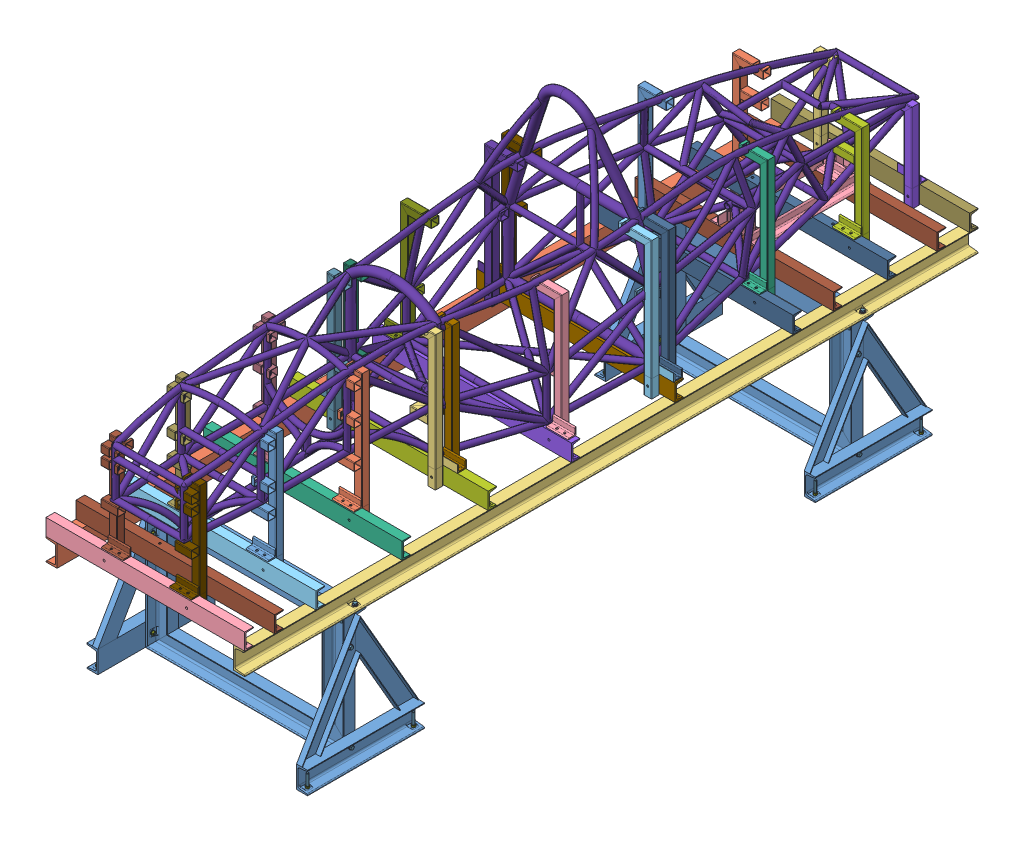
SolidWorks assembly FrameOnMainJig, configuration Default. Lengths in mm.
Overall size (1444.14 1755.21 3568.16).
235 component instances, 41 part files, 62 mates.
Components (placement in the parent):
- MainJig-1: MainJig [Default] at origin size (1000 753.95 3322.05)
  - MainJigLegs-1: MainJigLegs [Default<As Machined>] at origin size (1000 560 530)
  - MainJigLegs-2: MainJigLegs [Default<As Machined>] at (0 0 2300) size (1000 560 530)
  - MainJigLongRailRight-1: MainJigLongRailRight [Default<As Machined>] at (-400 50 2270) x (0 0 -1) z (1 0 0) size (3322 100 50)
  - MainJigLongRailLeft-1: MainJigLongRailLeft [Default<As Machined>] at (400 50 2270) x (0 0 -1) z (1 0 0) size (3322 100 50)
  - MainJigCrossRailA-1: MainJigCrossRailA [Default<As Machined>] at (0 137.5 2800) size (900 75 40)
  - MainJigCrossRailC-2: MainJigCrossRailC [Default<As Machined>] at (0 137.5 2477) size (900 75 40)
  - MainJigCrossRailD-3: MainJigCrossRailD [Default<As Machined>] at (0 137.5 2087.1) size (900 75 40)
  - MainJigCrossRailE-4: MainJigCrossRailE [Default<As Machined>] at (0 138.1 1697) size (900 76.2 38.05)
  - MainJigCrossRailF-5: MainJigCrossRailF [Default<As Machined>] at (0 138.1 1320) size (900 76.2 38.05)
  - MainJigCrossRailG-6: MainJigCrossRailG [Default<As Machined>] at (0 138.1 850) size (900 76.2 38.05)
  - MainJigCrossRailH-7: MainJigCrossRailH [Default<As Machined>] at (0 138.1 316.2) size (900 76.2 38.05)
  - MainJigCrossRail-8: MainJigCrossRail [Default<As Machined>] at (0 137.5 2664.3) size (900 75 40)
  - MainJigCrossRail-9: MainJigCrossRail [Default<As Machined>] at (0 137.5 132.6) size (900 75 40)
  - MainJigCrossRailH-10: MainJigCrossRailH [Default<As Machined>] at (0 138.1 -112.5) size (900 76.2 38.05)
  - MainJigCrossRail-11: MainJigCrossRail [Default<As Machined>] at (0 137.5 -336.9) size (900 75 40)
  - MainJigCrossRailL-12: MainJigCrossRailL [Default<As Machined>] at (0 138.1 -484) size (900 76.2 38.05)
  - Flat Washer Type A Narrow_AI-36: Flat Washer Type A Narrow_AI [Preferred Narrow FW 0.375] at (425 105 2780) x (0 -1 0) z (0 0 1) size (1.65 20.62 20.62)
  - Flat Washer Type A Narrow_AI-37: Flat Washer Type A Narrow_AI [Preferred Narrow FW 0.375] at (425 104 2457) x (0 -1 0) z (0 0 1) size (1.65 20.62 20.62)
  - Flat Washer Type A Narrow_AI-38: Flat Washer Type A Narrow_AI [Preferred Narrow FW 0.375] at (425 105 2067.1) x (0 -1 0) z (0 0 1) size (1.65 20.62 20.62)
  - Flat Washer Type A Narrow_AI-39: Flat Washer Type A Narrow_AI [Preferred Narrow FW 0.375] at (425 105 1677) x (0 -1 0) z (0 0 1) size (1.65 20.62 20.62)
  - Flat Washer Type A Narrow_AI-40: Flat Washer Type A Narrow_AI [Preferred Narrow FW 0.375] at (425 105 1300) x (0 -1 0) z (0 0 1) size (1.65 20.62 20.62)
  - Flat Washer Type A Narrow_AI-41: Flat Washer Type A Narrow_AI [Preferred Narrow FW 0.375] at (425 105 830) x (0 -1 0) z (0 0 1) size (1.65 20.62 20.62)
  - Flat Washer Type A Narrow_AI-42: Flat Washer Type A Narrow_AI [Preferred Narrow FW 0.375] at (425 105 2644.3) x (0 -1 0) z (0 0 1) size (1.65 20.62 20.62)
  - Flat Washer Type A Narrow_AI-43: Flat Washer Type A Narrow_AI [Preferred Narrow FW 0.375] at (425 105 296.2) x (0 -1 0) z (0 0 1) size (1.65 20.62 20.62)
  - Flat Washer Type A Narrow_AI-44: Flat Washer Type A Narrow_AI [Preferred Narrow FW 0.375] at (425 104.6 112.6) x (0 -1 0) z (0 0 1) size (1.65 20.62 20.62)
  - Flat Washer Type A Narrow_AI-45: Flat Washer Type A Narrow_AI [Preferred Narrow FW 0.375] at (425 105 -132.5) x (0 -1 0) z (0 0 1) size (1.65 20.62 20.62)
  - Flat Washer Type A Narrow_AI-46: Flat Washer Type A Narrow_AI [Preferred Narrow FW 0.375] at (425 104 -356.9) x (0 -1 0) z (0 0 1) size (1.65 20.62 20.62)
  - Flat Washer Type A Narrow_AI-48: Flat Washer Type A Narrow_AI [Preferred Narrow FW 0.375] at (425 105 -504) x (0 -1 0) z (0 0 1) size (1.65 20.62 20.62)
  - Flat Washer Type A Narrow_AI-49: Flat Washer Type A Narrow_AI [Preferred Narrow FW 0.375] at (-425 105 2780) x (0 -1 0) z (0 0 1) size (1.65 20.62 20.62)
  - Flat Washer Type A Narrow_AI-50: Flat Washer Type A Narrow_AI [Preferred Narrow FW 0.375] at (-425 105 2457) x (0 -1 0) z (0 0 1) size (1.65 20.62 20.62)
  - Flat Washer Type A Narrow_AI-51: Flat Washer Type A Narrow_AI [Preferred Narrow FW 0.375] at (-425 105 2067.1) x (0 -1 0) z (0 0 1) size (1.65 20.62 20.62)
  - Flat Washer Type A Narrow_AI-52: Flat Washer Type A Narrow_AI [Preferred Narrow FW 0.375] at (-425 105 1677) x (0 -1 0) z (0 0 1) size (1.65 20.62 20.62)
  - Flat Washer Type A Narrow_AI-53: Flat Washer Type A Narrow_AI [Preferred Narrow FW 0.375] at (-425 105 1300) x (0 -1 0) z (0 0 1) size (1.65 20.62 20.62)
  - Flat Washer Type A Narrow_AI-54: Flat Washer Type A Narrow_AI [Preferred Narrow FW 0.375] at (-425 105 830) x (0 -1 0) z (0 0 1) size (1.65 20.62 20.62)
  - Flat Washer Type A Narrow_AI-56: Flat Washer Type A Narrow_AI [Preferred Narrow FW 0.375] at (-425 105 2644.3) x (0 -1 0) z (0 0 1) size (1.65 20.62 20.62)
  - Flat Washer Type A Narrow_AI-57: Flat Washer Type A Narrow_AI [Preferred Narrow FW 0.375] at (-425 105 296.2) x (0 -1 0) z (0 0 1) size (1.65 20.62 20.62)
  - Flat Washer Type A Narrow_AI-58: Flat Washer Type A Narrow_AI [Preferred Narrow FW 0.375] at (-425 104.6 112.6) x (0 -1 0) z (0 0 1) size (1.65 20.62 20.62)
  - Flat Washer Type A Narrow_AI-59: Flat Washer Type A Narrow_AI [Preferred Narrow FW 0.375] at (-425 105 -132.5) x (0 -1 0) z (0 0 1) size (1.65 20.62 20.62)
  - Flat Washer Type A Narrow_AI-60: Flat Washer Type A Narrow_AI [Preferred Narrow FW 0.375] at (-425 104 -356.9) x (0 -1 0) z (0 0 1) size (1.65 20.62 20.62)
  - Flat Washer Type A Narrow_AI-61: Flat Washer Type A Narrow_AI [Preferred Narrow FW 0.375] at (-425 105 -504) x (0 -1 0) z (0 0 1) size (1.65 20.62 20.62)
  - Hex Bolt_AI-17: Hex Bolt_AI [HBOLT 0.3750-16x1.25x1-N] at (425 113.4582 2780) x (0 -1 0) z (0 0 1) size (38.56 16.48 14.27)
  - Hex Bolt_AI-18: Hex Bolt_AI [HBOLT 0.3750-16x1.25x1-N] at (425 112.4582 2457) x (0 -1 0) z (0 0 1) size (38.56 16.48 14.27)
  - Hex Bolt_AI-19: Hex Bolt_AI [HBOLT 0.3750-16x1.25x1-N] at (425 113.4582 2067.1) x (0 -1 0) z (0 0 1) size (38.56 16.48 14.27)
  - Hex Bolt_AI-20: Hex Bolt_AI [HBOLT 0.3750-16x1.25x1-N] at (425 113.4582 1677) x (0 -1 0) z (0 0 1) size (38.56 16.48 14.27)
  - Hex Bolt_AI-21: Hex Bolt_AI [HBOLT 0.3750-16x1.25x1-N] at (425 113.4582 1300) x (0 -1 0) z (0 0 1) size (38.56 16.48 14.27)
  - Hex Bolt_AI-22: Hex Bolt_AI [HBOLT 0.3750-16x1.25x1-N] at (425 113.4582 830) x (0 -1 0) z (0 0 1) size (38.56 16.48 14.27)
  - Hex Bolt_AI-23: Hex Bolt_AI [HBOLT 0.3750-16x1.25x1-N] at (425 113.4582 2644.3) x (0 -1 0) z (0 0 1) size (38.56 16.48 14.27)
  - Hex Bolt_AI-24: Hex Bolt_AI [HBOLT 0.3750-16x1.25x1-N] at (425 113.4582 296.2) x (0 -1 0) z (0 0 1) size (38.56 16.48 14.27)
  - Hex Bolt_AI-25: Hex Bolt_AI [HBOLT 0.3750-16x1.25x1-N] at (425 113.0582 112.6) x (0 -1 0) z (0 0 1) size (38.56 16.48 14.27)
  - Hex Bolt_AI-26: Hex Bolt_AI [HBOLT 0.3750-16x1.25x1-N] at (425 113.4582 -132.5) x (0 -1 0) z (0 0 1) size (38.56 16.48 14.27)
  - Hex Bolt_AI-27: Hex Bolt_AI [HBOLT 0.3750-16x1.25x1-N] at (425 112.4582 -356.9) x (0 -1 0) z (0 0 1) size (38.56 16.48 14.27)
  - Hex Bolt_AI-28: Hex Bolt_AI [HBOLT 0.3750-16x1.25x1-N] at (425 113.4582 -504) x (0 -1 0) z (0 0 1) size (38.56 16.48 14.27)
  - Hex Bolt_AI-29: Hex Bolt_AI [HBOLT 0.3750-16x1.25x1-N] at (-425 113.4582 2780) x (0 -1 0) z (0 0 1) size (38.56 16.48 14.27)
  - Hex Bolt_AI-30: Hex Bolt_AI [HBOLT 0.3750-16x1.25x1-N] at (-425 113.4582 2457) x (0 -1 0) z (0 0 1) size (38.56 16.48 14.27)
  - Hex Bolt_AI-31: Hex Bolt_AI [HBOLT 0.3750-16x1.25x1-N] at (-425 113.4582 2067.1) x (0 -1 0) z (0 0 1) size (38.56 16.48 14.27)
  - Hex Bolt_AI-32: Hex Bolt_AI [HBOLT 0.3750-16x1.25x1-N] at (-425 113.4582 1677) x (0 -1 0) z (0 0 1) size (38.56 16.48 14.27)
  - Hex Bolt_AI-33: Hex Bolt_AI [HBOLT 0.3750-16x1.25x1-N] at (-425 113.4582 1300) x (0 -1 0) z (0 0 1) size (38.56 16.48 14.27)
  - Hex Bolt_AI-34: Hex Bolt_AI [HBOLT 0.3750-16x1.25x1-N] at (-425 113.4582 830) x (0 -1 0) z (0 0 1) size (38.56 16.48 14.27)
  - Hex Bolt_AI-35: Hex Bolt_AI [HBOLT 0.3750-16x1.25x1-N] at (-425 113.4582 2644.3) x (0 -1 0) z (0 0 1) size (38.56 16.48 14.27)
  - Hex Bolt_AI-36: Hex Bolt_AI [HBOLT 0.3750-16x1.25x1-N] at (-425 113.4582 296.2) x (0 -1 0) z (0 0 1) size (38.56 16.48 14.27)
  - Hex Bolt_AI-37: Hex Bolt_AI [HBOLT 0.3750-16x1.25x1-N] at (-425 113.0582 112.6) x (0 -1 0) z (0 0 1) size (38.56 16.48 14.27)
  - Hex Bolt_AI-38: Hex Bolt_AI [HBOLT 0.3750-16x1.25x1-N] at (-425 113.4582 -132.5) x (0 -1 0) z (0 0 1) size (38.56 16.48 14.27)
  - Hex Bolt_AI-39: Hex Bolt_AI [HBOLT 0.3750-16x1.25x1-N] at (-425 112.4582 -356.9) x (0 -1 0) z (0 0 1) size (38.56 16.48 14.27)
  - Hex Bolt_AI-40: Hex Bolt_AI [HBOLT 0.3750-16x1.25x1-N] at (-425 113.4582 -504) x (0 -1 0) z (0 0 1) size (38.56 16.48 14.27)
  - Lock Washer Spring Regular_AI-68: Lock Washer Spring Regular_AI [Regular LW 0.375] at (425 93 2780) x (0 1 0) z (0 0 1) size (2.39 17.35 17.32)
  - Lock Washer Spring Regular_AI-69: Lock Washer Spring Regular_AI [Regular LW 0.375] at (425 93 2644.3) x (0 1 0) z (0 0 1) size (2.39 17.35 17.32)
  - Lock Washer Spring Regular_AI-70: Lock Washer Spring Regular_AI [Regular LW 0.375] at (425 93 2457) x (0 1 0) z (0 0 1) size (2.39 17.35 17.32)
  - Lock Washer Spring Regular_AI-71: Lock Washer Spring Regular_AI [Regular LW 0.375] at (425 93 2067.1) x (0 1 0) z (0 0 1) size (2.39 17.35 17.32)
  - Lock Washer Spring Regular_AI-72: Lock Washer Spring Regular_AI [Regular LW 0.375] at (425 93 1677) x (0 1 0) z (0 0 1) size (2.39 17.35 17.32)
  - Lock Washer Spring Regular_AI-73: Lock Washer Spring Regular_AI [Regular LW 0.375] at (425 93 1300) x (0 1 0) z (0 0 1) size (2.39 17.35 17.32)
  - Lock Washer Spring Regular_AI-74: Lock Washer Spring Regular_AI [Regular LW 0.375] at (425 93 830) x (0 1 0) z (0 0 1) size (2.39 17.35 17.32)
  - Lock Washer Spring Regular_AI-75: Lock Washer Spring Regular_AI [Regular LW 0.375] at (425 93 296.2) x (0 1 0) z (0 0 1) size (2.39 17.35 17.32)
  - Lock Washer Spring Regular_AI-76: Lock Washer Spring Regular_AI [Regular LW 0.375] at (425 93 112.6) x (0 1 0) z (0 0 1) size (2.39 17.35 17.32)
  - Lock Washer Spring Regular_AI-78: Lock Washer Spring Regular_AI [Regular LW 0.375] at (425 93 -132.5) x (0 1 0) z (0 0 1) size (2.39 17.35 17.32)
  - Lock Washer Spring Regular_AI-79: Lock Washer Spring Regular_AI [Regular LW 0.375] at (425 93 -356.9) x (0 1 0) z (0 0 1) size (2.39 17.35 17.32)
  - Lock Washer Spring Regular_AI-80: Lock Washer Spring Regular_AI [Regular LW 0.375] at (425 93 -504) x (0 1 0) z (0 0 1) size (2.39 17.35 17.32)
  - Lock Washer Spring Regular_AI-81: Lock Washer Spring Regular_AI [Regular LW 0.375] at (-425 93 2780) x (0 1 0) z (0 0 1) size (2.39 17.35 17.32)
  - Lock Washer Spring Regular_AI-82: Lock Washer Spring Regular_AI [Regular LW 0.375] at (-425 93 2644.3) x (0 1 0) z (0 0 1) size (2.39 17.35 17.32)
  - Lock Washer Spring Regular_AI-83: Lock Washer Spring Regular_AI [Regular LW 0.375] at (-425 93 2457) x (0 1 0) z (0 0 1) size (2.39 17.35 17.32)
  - Lock Washer Spring Regular_AI-84: Lock Washer Spring Regular_AI [Regular LW 0.375] at (-425 93 2067.1) x (0 1 0) z (0 0 1) size (2.39 17.35 17.32)
  - Lock Washer Spring Regular_AI-85: Lock Washer Spring Regular_AI [Regular LW 0.375] at (-425 93 1677) x (0 1 0) z (0 0 1) size (2.39 17.35 17.32)
  - Lock Washer Spring Regular_AI-86: Lock Washer Spring Regular_AI [Regular LW 0.375] at (-425 93 1300) x (0 1 0) z (0 0 1) size (2.39 17.35 17.32)
  - Lock Washer Spring Regular_AI-87: Lock Washer Spring Regular_AI [Regular LW 0.375] at (-425 93 830) x (0 1 0) z (0 0 1) size (2.39 17.35 17.32)
  - Lock Washer Spring Regular_AI-88: Lock Washer Spring Regular_AI [Regular LW 0.375] at (-425 93 296.2) x (0 1 0) z (0 0 1) size (2.39 17.35 17.32)
  - Lock Washer Spring Regular_AI-89: Lock Washer Spring Regular_AI [Regular LW 0.375] at (-425 93 112.6) x (0 1 0) z (0 0 1) size (2.39 17.35 17.32)
  - Lock Washer Spring Regular_AI-90: Lock Washer Spring Regular_AI [Regular LW 0.375] at (-425 93 -132.5) x (0 1 0) z (0 0 1) size (2.39 17.35 17.32)
  - Lock Washer Spring Regular_AI-91: Lock Washer Spring Regular_AI [Regular LW 0.375] at (-425 93 -356.9) x (0 1 0) z (0 0 1) size (2.39 17.35 17.32)
  - Lock Washer Spring Regular_AI-92: Lock Washer Spring Regular_AI [Regular LW 0.375] at (-425 93 -504) x (0 1 0) z (0 0 1) size (2.39 17.35 17.32)
  - Hex Nut_AI-92: Hex Nut_AI [HNUT 0.3750-16-D-N] at (425 82.0526 2780) x (1 0 0) z (0 -1 0) size (14.27 16.48 8.56)
  - Hex Nut_AI-93: Hex Nut_AI [HNUT 0.3750-16-D-N] at (425 82.0526 2644.3) x (1 0 0) z (0 -1 0) size (14.27 16.48 8.56)
  - Hex Nut_AI-94: Hex Nut_AI [HNUT 0.3750-16-D-N] at (425 82.0526 2457) x (1 0 0) z (0 -1 0) size (14.27 16.48 8.56)
  - Hex Nut_AI-95: Hex Nut_AI [HNUT 0.3750-16-D-N] at (425 82.0526 2067.1) x (1 0 0) z (0 -1 0) size (14.27 16.48 8.56)
  - Hex Nut_AI-96: Hex Nut_AI [HNUT 0.3750-16-D-N] at (425 82.0526 1677) x (1 0 0) z (0 -1 0) size (14.27 16.48 8.56)
  - Hex Nut_AI-97: Hex Nut_AI [HNUT 0.3750-16-D-N] at (425 82.0526 1300) x (1 0 0) z (0 -1 0) size (14.27 16.48 8.56)
  - Hex Nut_AI-98: Hex Nut_AI [HNUT 0.3750-16-D-N] at (425 82.0526 830) x (1 0 0) z (0 -1 0) size (14.27 16.48 8.56)
  - Hex Nut_AI-99: Hex Nut_AI [HNUT 0.3750-16-D-N] at (425 82.0526 296.2) x (1 0 0) z (0 -1 0) size (14.27 16.48 8.56)
  - Hex Nut_AI-100: Hex Nut_AI [HNUT 0.3750-16-D-N] at (425 82.0526 112.6) x (1 0 0) z (0 -1 0) size (14.27 16.48 8.56)
  - Hex Nut_AI-101: Hex Nut_AI [HNUT 0.3750-16-D-N] at (425 82.0526 -132.5) x (1 0 0) z (0 -1 0) size (14.27 16.48 8.56)
  - Hex Nut_AI-102: Hex Nut_AI [HNUT 0.3750-16-D-N] at (425 82.0526 -356.9) x (1 0 0) z (0 -1 0) size (14.27 16.48 8.56)
  - Hex Nut_AI-103: Hex Nut_AI [HNUT 0.3750-16-D-N] at (425 82.0526 -504) x (1 0 0) z (0 -1 0) size (14.27 16.48 8.56)
  - Hex Nut_AI-104: Hex Nut_AI [HNUT 0.3750-16-D-N] at (-425 82.0526 2780) x (1 0 0) z (0 -1 0) size (14.27 16.48 8.56)
  - Hex Nut_AI-105: Hex Nut_AI [HNUT 0.3750-16-D-N] at (-425 82.0526 2644.3) x (1 0 0) z (0 -1 0) size (14.27 16.48 8.56)
  - Hex Nut_AI-106: Hex Nut_AI [HNUT 0.3750-16-D-N] at (-425 82.0526 2457) x (1 0 0) z (0 -1 0) size (14.27 16.48 8.56)
  - Hex Nut_AI-107: Hex Nut_AI [HNUT 0.3750-16-D-N] at (-425 82.0526 2067.1) x (1 0 0) z (0 -1 0) size (14.27 16.48 8.56)
  - Hex Nut_AI-108: Hex Nut_AI [HNUT 0.3750-16-D-N] at (-425 82.0526 1677) x (1 0 0) z (0 -1 0) size (14.27 16.48 8.56)
  - Hex Nut_AI-109: Hex Nut_AI [HNUT 0.3750-16-D-N] at (-425 82.0526 1300) x (1 0 0) z (0 -1 0) size (14.27 16.48 8.56)
  - Hex Nut_AI-110: Hex Nut_AI [HNUT 0.3750-16-D-N] at (-425 82.0526 830) x (1 0 0) z (0 -1 0) size (14.27 16.48 8.56)
  - Hex Nut_AI-111: Hex Nut_AI [HNUT 0.3750-16-D-N] at (-425 82.0526 296.2) x (1 0 0) z (0 -1 0) size (14.27 16.48 8.56)
  - Hex Nut_AI-112: Hex Nut_AI [HNUT 0.3750-16-D-N] at (-425 82.0526 112.6) x (1 0 0) z (0 -1 0) size (14.27 16.48 8.56)
  - Hex Nut_AI-113: Hex Nut_AI [HNUT 0.3750-16-D-N] at (-425 82.0526 -132.5) x (1 0 0) z (0 -1 0) size (14.27 16.48 8.56)
  - Hex Nut_AI-114: Hex Nut_AI [HNUT 0.3750-16-D-N] at (-425 82.0526 -356.9) x (1 0 0) z (0 -1 0) size (14.27 16.48 8.56)
  - Hex Nut_AI-115: Hex Nut_AI [HNUT 0.3750-16-D-N] at (-425 82.0526 -504) x (1 0 0) z (0 -1 0) size (14.27 16.48 8.56)
  - Flat Washer Type A Narrow_AI-62: Flat Washer Type A Narrow_AI [Preferred Narrow FW 0.375] at (-453 -119.3078 25) size (1.65 20.62 20.62)
  - Flat Washer Type A Narrow_AI-63: Flat Washer Type A Narrow_AI [Preferred Narrow FW 0.375] at (-455.9 -510 25) size (1.65 20.62 20.62)
  - Flat Washer Type A Narrow_AI-64: Flat Washer Type A Narrow_AI [Preferred Narrow FW 0.375] at (453 -119.3078 25) x (-1 0 0) z (0 0.924225 0.381849) size (1.65 20.62 20.62)
  - Flat Washer Type A Narrow_AI-65: Flat Washer Type A Narrow_AI [Preferred Narrow FW 0.375] at (455.9 -510 25) x (-1 0 0) z (0 0.924225 0.381849) size (1.65 20.62 20.62)
  - Flat Washer Type A Narrow_AI-66: Flat Washer Type A Narrow_AI [Preferred Narrow FW 0.375] at (453 -119.3078 2325) x (-1 0 0) z (0 0.924225 0.381849) size (1.65 20.62 20.62)
  - Flat Washer Type A Narrow_AI-67: Flat Washer Type A Narrow_AI [Preferred Narrow FW 0.375] at (455.9 -510 2325) x (-1 0 0) z (0 0.924225 0.381849) size (1.65 20.62 20.62)
  - Flat Washer Type A Narrow_AI-68: Flat Washer Type A Narrow_AI [Preferred Narrow FW 0.375] at (-453 -119.3078 2325) size (1.65 20.62 20.62)
  - Flat Washer Type A Narrow_AI-69: Flat Washer Type A Narrow_AI [Preferred Narrow FW 0.375] at (-455.9 -510 2325) size (1.65 20.62 20.62)
  - Flat Washer Type A Narrow_AI-70: Flat Washer Type A Narrow_AI [Preferred Narrow FW 0.375] at (-400 -50 2305.9) x (0 0 -1) z (1 0 0) size (1.65 20.62 20.62)
  - Flat Washer Type A Narrow_AI-71: Flat Washer Type A Narrow_AI [Preferred Narrow FW 0.375] at (400 -50 2305.9) x (0 0 -1) z (1 0 0) size (1.65 20.62 20.62)
  - Flat Washer Type A Narrow_AI-72: Flat Washer Type A Narrow_AI [Preferred Narrow FW 0.375] at (-400 -50 5.9) x (0 0 -1) z (1 0 0) size (1.65 20.62 20.62)
  - Flat Washer Type A Narrow_AI-73: Flat Washer Type A Narrow_AI [Preferred Narrow FW 0.375] at (400 -50 5.9) x (0 0 -1) z (1 0 0) size (1.65 20.62 20.62)
  - Flat Washer Type A Narrow_AI-74: Flat Washer Type A Narrow_AI [Preferred Narrow FW 0.375] at (425 7 2275) x (0 -1 0) z (0 0 1) size (1.65 20.62 20.62)
  - Flat Washer Type A Narrow_AI-75: Flat Washer Type A Narrow_AI [Preferred Narrow FW 0.375] at (425 7 -25) x (0 -1 0) z (0 0 1) size (1.65 20.62 20.62)
  - Flat Washer Type A Narrow_AI-76: Flat Washer Type A Narrow_AI [Preferred Narrow FW 0.375] at (-425 7 -25) x (0 -1 0) z (0 0 1) size (1.65 20.62 20.62)
  - Flat Washer Type A Narrow_AI-77: Flat Washer Type A Narrow_AI [Preferred Narrow FW 0.375] at (-425 7 2275) x (0 -1 0) z (0 0 1) size (1.65 20.62 20.62)
  - Lock Washer Spring Regular_AI-93: Lock Washer Spring Regular_AI [Regular LW 0.375] at (-425 -6.4843 2275) x (0 1 0) z (0 0 1) size (2.39 17.35 17.32)
  - Lock Washer Spring Regular_AI-94: Lock Washer Spring Regular_AI [Regular LW 0.375] at (-400 -50 2294.1) x (0 0 1) z (-1 0 0) size (2.39 17.35 17.32)
  - Lock Washer Spring Regular_AI-95: Lock Washer Spring Regular_AI [Regular LW 0.375] at (400 -50 2294.1) x (0 0 1) z (-1 0 0) size (2.39 17.35 17.32)
  - Lock Washer Spring Regular_AI-96: Lock Washer Spring Regular_AI [Regular LW 0.375] at (425 -6.4843 2275) x (0 1 0) z (0 0 1) size (2.39 17.35 17.32)
  - Lock Washer Spring Regular_AI-97: Lock Washer Spring Regular_AI [Regular LW 0.375] at (443 -119.3078 2325) size (2.39 17.35 17.32)
  - Lock Washer Spring Regular_AI-98: Lock Washer Spring Regular_AI [Regular LW 0.375] at (443 -510 2325) size (2.39 17.35 17.32)
  - Lock Washer Spring Regular_AI-99: Lock Washer Spring Regular_AI [Regular LW 0.375] at (-443 -119.3078 2325) x (-1 0 0) z (0 0.924225 0.381849) size (2.39 17.35 17.32)
  - Lock Washer Spring Regular_AI-100: Lock Washer Spring Regular_AI [Regular LW 0.375] at (-443 -510 2325) x (-1 0 0) z (0 0.924225 0.381849) size (2.39 17.35 17.32)
  - Lock Washer Spring Regular_AI-101: Lock Washer Spring Regular_AI [Regular LW 0.375] at (-475 -560 2540) x (0 1 0) z (0 0 1) size (2.39 17.35 17.32)
  - Lock Washer Spring Regular_AI-102: Lock Washer Spring Regular_AI [Regular LW 0.375] at (-475 -560 2060) x (0 1 0) z (0 0 1) size (2.39 17.35 17.32)
  - Lock Washer Spring Regular_AI-103: Lock Washer Spring Regular_AI [Regular LW 0.375] at (475 -560 2060) x (0 1 0) z (0 0 1) size (2.39 17.35 17.32)
  - Lock Washer Spring Regular_AI-104: Lock Washer Spring Regular_AI [Regular LW 0.375] at (475 -560 2540) x (0 1 0) z (0 0 1) size (2.39 17.35 17.32)
  - Lock Washer Spring Regular_AI-105: Lock Washer Spring Regular_AI [Regular LW 0.375] at (425 -6.4843 -25) x (0 1 0) z (0 0 1) size (2.39 17.35 17.32)
  - Lock Washer Spring Regular_AI-106: Lock Washer Spring Regular_AI [Regular LW 0.375] at (400 -50 -5.9) x (0 0 1) z (-1 0 0) size (2.39 17.35 17.32)
  - Lock Washer Spring Regular_AI-107: Lock Washer Spring Regular_AI [Regular LW 0.375] at (-400 -50 -5.9) x (0 0 1) z (-1 0 0) size (2.39 17.35 17.32)
  - Lock Washer Spring Regular_AI-108: Lock Washer Spring Regular_AI [Regular LW 0.375] at (-425 -6.4843 -25) x (0 1 0) z (0 0 1) size (2.39 17.35 17.32)
  - Lock Washer Spring Regular_AI-109: Lock Washer Spring Regular_AI [Regular LW 0.375] at (-443 -119.3078 25) x (-1 0 0) z (0 0.924225 0.381849) size (2.39 17.35 17.32)
  - Lock Washer Spring Regular_AI-110: Lock Washer Spring Regular_AI [Regular LW 0.375] at (-443 -510 25) x (-1 0 0) z (0 0.924225 0.381849) size (2.39 17.35 17.32)
  - Lock Washer Spring Regular_AI-111: Lock Washer Spring Regular_AI [Regular LW 0.375] at (443 -119.3078 25) size (2.39 17.35 17.32)
  - Lock Washer Spring Regular_AI-112: Lock Washer Spring Regular_AI [Regular LW 0.375] at (443 -510 25) size (2.39 17.35 17.32)
  - Lock Washer Spring Regular_AI-113: Lock Washer Spring Regular_AI [Regular LW 0.375] at (-475 -560 -240) x (0 1 0) z (0 0 1) size (2.39 17.35 17.32)
  - Lock Washer Spring Regular_AI-114: Lock Washer Spring Regular_AI [Regular LW 0.375] at (-475 -560 240) x (0 1 0) z (0 0 1) size (2.39 17.35 17.32)
  - Lock Washer Spring Regular_AI-115: Lock Washer Spring Regular_AI [Regular LW 0.375] at (475 -560 240) x (0 1 0) z (0 0 1) size (2.39 17.35 17.32)
  - Lock Washer Spring Regular_AI-116: Lock Washer Spring Regular_AI [Regular LW 0.375] at (475 -560 -240) x (0 1 0) z (0 0 1) size (2.39 17.35 17.32)
  - Hex Nut_AI-116: Hex Nut_AI [HNUT 0.3750-16-D-N] at (425 -17.4317 -25) x (1 0 0) z (0 -1 0) size (14.27 16.48 8.56)
  - Hex Nut_AI-117: Hex Nut_AI [HNUT 0.3750-16-D-N] at (400 -50 -16.8474) x (0.923728 0.383049 0) z (0 0 -1) size (14.27 16.48 8.56)
  - Hex Nut_AI-118: Hex Nut_AI [HNUT 0.3750-16-D-N] at (-425 -17.4317 -25) x (1 0 0) z (0 -1 0) size (14.27 16.48 8.56)
  - Hex Nut_AI-119: Hex Nut_AI [HNUT 0.3750-16-D-N] at (-400 -50 -16.8474) x (0.923728 0.383049 0) z (0 0 -1) size (14.27 16.48 8.56)
  - Hex Nut_AI-120: Hex Nut_AI [HNUT 0.3750-16-D-N] at (432.0526 -119.3078 25) x (0 0 1) z (-1 0 0) size (14.27 16.48 8.56)
  - Hex Nut_AI-121: Hex Nut_AI [HNUT 0.3750-16-D-N] at (432.0526 -510 25) x (0 0 1) z (-1 0 0) size (14.27 16.48 8.56)
  - Hex Nut_AI-122: Hex Nut_AI [HNUT 0.3750-16-D-N] at (-432.0526 -119.3078 25) x (0 0 -1) z (1 0 0) size (14.27 16.48 8.56)
  - Hex Nut_AI-123: Hex Nut_AI [HNUT 0.3750-16-D-N] at (-432.0526 -510 25) x (0 0 -1) z (1 0 0) size (14.27 16.48 8.56)
  - Hex Nut_AI-124: Hex Nut_AI [HNUT 0.3750-16-D-N] at (475 -570.9474 240) x (1 0 0) z (0 -1 0) size (14.27 16.48 8.56)
  - Hex Nut_AI-125: Hex Nut_AI [HNUT 0.3750-16-D-N] at (475 -570.9474 -240) x (1 0 0) z (0 -1 0) size (14.27 16.48 8.56)
  - Hex Nut_AI-126: Hex Nut_AI [HNUT 0.3750-16-D-N] at (-475 -570.9474 -240) x (1 0 0) z (0 -1 0) size (14.27 16.48 8.56)
  - Hex Nut_AI-127: Hex Nut_AI [HNUT 0.3750-16-D-N] at (-475 -570.9474 240) x (1 0 0) z (0 -1 0) size (14.27 16.48 8.56)
  - Hex Nut_AI-128: Hex Nut_AI [HNUT 0.3750-16-D-N] at (475 -544.4402 240) x (1 0 0) z (0 1 0) size (14.27 16.48 8.56)
  - Hex Nut_AI-129: Hex Nut_AI [HNUT 0.3750-16-D-N] at (475 -544.4402 -240) x (1 0 0) z (0 1 0) size (14.27 16.48 8.56)
  - Hex Nut_AI-130: Hex Nut_AI [HNUT 0.3750-16-D-N] at (-475 -544.4402 -240) x (1 0 0) z (0 1 0) size (14.27 16.48 8.56)
  - Hex Nut_AI-131: Hex Nut_AI [HNUT 0.3750-16-D-N] at (-475 -544.4402 240) x (1 0 0) z (0 1 0) size (14.27 16.48 8.56)
  - Hex Nut_AI-132: Hex Nut_AI [HNUT 0.3750-16-D-N] at (425 -17.4317 2275) x (1 0 0) z (0 -1 0) size (14.27 16.48 8.56)
  - Hex Nut_AI-133: Hex Nut_AI [HNUT 0.3750-16-D-N] at (400 -50 2283.1526) x (0.923728 0.383049 0) z (0 0 -1) size (14.27 16.48 8.56)
  - Hex Nut_AI-134: Hex Nut_AI [HNUT 0.3750-16-D-N] at (-425 -17.4317 2275) x (1 0 0) z (0 -1 0) size (14.27 16.48 8.56)
  - Hex Nut_AI-135: Hex Nut_AI [HNUT 0.3750-16-D-N] at (-400 -50 2283.1526) x (0.923728 0.383049 0) z (0 0 -1) size (14.27 16.48 8.56)
  - Hex Nut_AI-136: Hex Nut_AI [HNUT 0.3750-16-D-N] at (-432.0526 -119.3078 2325) x (0 0 -1) z (1 0 0) size (14.27 16.48 8.56)
  - Hex Nut_AI-137: Hex Nut_AI [HNUT 0.3750-16-D-N] at (-432.0526 -510 2325) x (0 0 -1) z (1 0 0) size (14.27 16.48 8.56)
  - Hex Nut_AI-138: Hex Nut_AI [HNUT 0.3750-16-D-N] at (432.0526 -510 2325) x (0 0 1) z (-1 0 0) size (14.27 16.48 8.56)
  - Hex Nut_AI-139: Hex Nut_AI [HNUT 0.3750-16-D-N] at (432.0526 -119.3078 2325) x (0 0 1) z (-1 0 0) size (14.27 16.48 8.56)
  - Hex Nut_AI-140: Hex Nut_AI [HNUT 0.3750-16-D-N] at (-475 -570.9474 2060) x (1 0 0) z (0 -1 0) size (14.27 16.48 8.56)
  - Hex Nut_AI-141: Hex Nut_AI [HNUT 0.3750-16-D-N] at (-475 -570.9474 2540) x (1 0 0) z (0 -1 0) size (14.27 16.48 8.56)
  - Hex Nut_AI-142: Hex Nut_AI [HNUT 0.3750-16-D-N] at (475 -570.9474 2540) x (1 0 0) z (0 -1 0) size (14.27 16.48 8.56)
  - Hex Nut_AI-143: Hex Nut_AI [HNUT 0.3750-16-D-N] at (475 -570.9474 2060) x (1 0 0) z (0 -1 0) size (14.27 16.48 8.56)
  - Hex Nut_AI-144: Hex Nut_AI [HNUT 0.3750-16-D-N] at (-475 -544.4402 2060) x (1 0 0) z (0 1 0) size (14.27 16.48 8.56)
  - Hex Nut_AI-145: Hex Nut_AI [HNUT 0.3750-16-D-N] at (-475 -544.4402 2540) x (1 0 0) z (0 1 0) size (14.27 16.48 8.56)
  - Hex Nut_AI-146: Hex Nut_AI [HNUT 0.3750-16-D-N] at (475 -544.4402 2540) x (1 0 0) z (0 1 0) size (14.27 16.48 8.56)
  - Hex Nut_AI-147: Hex Nut_AI [HNUT 0.3750-16-D-N] at (475 -544.4402 2060) x (1 0 0) z (0 1 0) size (14.27 16.48 8.56)
  - Hex Bolt_AI-41: Hex Bolt_AI [HBOLT 0.3750-16x1.25x1-N] at (425 15.4582 -25) x (0 -1 0) z (0 0 1) size (38.56 16.48 14.27)
  - Hex Bolt_AI-42: Hex Bolt_AI [HBOLT 0.3750-16x1.25x1-N] at (400 -50 14.3582) x (0 0 -1) z (1 0 0) size (38.56 16.48 14.27)
  - Hex Bolt_AI-43: Hex Bolt_AI [HBOLT 0.3750-16x1.25x1-N] at (461.4582 -119.3078 25) x (-1 0 0) z (0 0.924225 0.381849) size (38.56 16.48 14.27)
  - Hex Bolt_AI-44: Hex Bolt_AI [HBOLT 0.3750-16x1.25x1-N] at (464.3582 -510 25) x (-1 0 0) z (0 0.924225 0.381849) size (38.56 16.48 14.27)
  - Hex Bolt_AI-45: Hex Bolt_AI [HBOLT 0.3750-16x1.25x1-N] at (-400 -50 14.3582) x (0 0 -1) z (1 0 0) size (38.56 16.48 14.27)
  - Hex Bolt_AI-46: Hex Bolt_AI [HBOLT 0.3750-16x1.25x1-N] at (-461.4582 -119.3078 25) size (38.56 16.48 14.27)
  - Hex Bolt_AI-47: Hex Bolt_AI [HBOLT 0.3750-16x1.25x1-N] at (-464.3582 -510 25) size (38.56 16.48 14.27)
  - Hex Bolt_AI-48: Hex Bolt_AI [HBOLT 0.3750-16x1.25x1-N] at (-425 15.4582 -25) x (0 -1 0) z (0 0 1) size (38.56 16.48 14.27)
  - Hex Bolt_AI-49: Hex Bolt_AI [HBOLT 0.3750-16x1.25x1-N] at (425 15.4582 2275) x (0 -1 0) z (0 0 1) size (38.56 16.48 14.27)
  - Hex Bolt_AI-50: Hex Bolt_AI [HBOLT 0.3750-16x1.25x1-N] at (461.4582 -119.3078 2325) x (-1 0 0) z (0 0.924225 0.381849) size (38.56 16.48 14.27)
  - Hex Bolt_AI-52: Hex Bolt_AI [HBOLT 0.3750-16x1.25x1-N] at (464.3582 -510 2325) x (-1 0 0) z (0 0.924225 0.381849) size (38.56 16.48 14.27)
  - Hex Bolt_AI-53: Hex Bolt_AI [HBOLT 0.3750-16x1.125x1-N] at (400 -50 2314.3582) x (0 0 -1) z (1 0 0) size (35.38 16.48 14.27)
  - Hex Bolt_AI-54: Hex Bolt_AI [HBOLT 0.3750-16x1.125x1-N] at (-400 -50 2314.3582) x (0 0 -1) z (1 0 0) size (35.38 16.48 14.27)
  - Hex Bolt_AI-55: Hex Bolt_AI [HBOLT 0.3750-16x1.125x1-N] at (-461.4582 -119.3078 2325) size (35.38 16.48 14.27)
  - Hex Bolt_AI-56: Hex Bolt_AI [HBOLT 0.3750-16x1.125x1-N] at (-464.3582 -510 2325) size (35.38 16.48 14.27)
  - Hex Bolt_AI-57: Hex Bolt_AI [HBOLT 0.3750-16x1.125x1-N] at (-425 15.4582 2275) x (0 -1 0) z (0 0 1) size (35.38 16.48 14.27)
  - Hex Bolt_AI-58: Hex Bolt_AI [HBOLT 0.3750-16x3x1-N] at (475 -577.7546 2540) x (0 1 0) z (0 0 1) size (83.01 16.48 14.27)
  - Hex Bolt_AI-59: Hex Bolt_AI [HBOLT 0.3750-16x3x1-N] at (475 -577.7546 2060) x (0 1 0) z (0 0 1) size (83.01 16.48 14.27)
  - Hex Bolt_AI-60: Hex Bolt_AI [HBOLT 0.3750-16x3x1-N] at (-475 -577.7546 2540) x (0 1 0) z (0 0 1) size (83.01 16.48 14.27)
  - Hex Bolt_AI-61: Hex Bolt_AI [HBOLT 0.3750-16x3x1-N] at (-475 -577.7546 2060) x (0 1 0) z (0 0 1) size (83.01 16.48 14.27)
  - Hex Bolt_AI-62: Hex Bolt_AI [HBOLT 0.3750-16x3x1-N] at (-475 -577.7546 240) x (0 1 0) z (0 0 1) size (83.01 16.48 14.27)
  - Hex Bolt_AI-63: Hex Bolt_AI [HBOLT 0.3750-16x3x1-N] at (-475 -577.7546 -240) x (0 1 0) z (0 0 1) size (83.01 16.48 14.27)
  - Hex Bolt_AI-64: Hex Bolt_AI [HBOLT 0.3750-16x3x1-N] at (475 -577.7546 240) x (0 1 0) z (0 0 1) size (83.01 16.48 14.27)
  - Hex Bolt_AI-65: Hex Bolt_AI [HBOLT 0.3750-16x3x1-N] at (475 -577.7546 -240) x (0 1 0) z (0 0 1) size (83.01 16.48 14.27)
- Frame-1: Frame [Default<As Machined>] at (0 114.7 2380) x (0 0 -1) z (1 0 0) size (3568.16 1342.58 1352.9)
- JigTopRailALeft-1: JigTopRailALeft [Default<As Machined>] at (0 175 2742.1) size (100 509.9 71.6)
- JigTopRailCLeft-1: JigTopRailCLeft [Default<As Machined>] at (0 175 2419.1) size (100 565.9 71.6)
- JigTopRailDLeft-1: JigTopRailDLeft [Default<As Machined>] at (0 175 2029.2) size (100 605.9 71.6)
- JigTopRailE1Left-1: JigTopRailE1Left [Default<As Machined>] at (0 176.2 1714.9) size (180 608.9 70.8)
- JigTopRailFLeft-1: JigTopRailFLeft [Default<As Machined>] at (0 176.2 1262.1) size (204.2 597.9 70.8)
- JigTopRailG1Left-1: JigTopRailG1Left [Default<As Machined>] at (0 176.2 867.9) size (214.2 621.9 70.8)
- JigTopRailHLeft-1: JigTopRailHLeft [Default<As Machined>] at (0 176.2 258.3) size (130 589.5 70.8)
- JigTopRailJLeft-1: JigTopRailJLeft [Default<As Machined>] at (0 176.2 -170.4) size (140 519.8 70.8)
- JigTopRailLLeft-1: JigTopRailLLeft [Default<As Machined>] at (0 176.2 -466.1) size (100 399.9 70.8)
- JigTopRailE2Left-1: JigTopRailE2Left [Default<As Machined>] at (0 176.2 1639.1) size (144.2 606.9 70.8)
- JigTopRailG2Left-1: JigTopRailG2Left [Default<As Machined>] at (0 176.2 792.1) size (214.2 623.9 70.8)
- JigTopRailARight-1: JigTopRailARight [Default<As Machined>] at (0 175 2742.1) size (100 509.9 71.6)
- JigTopRailCRight-1: JigTopRailCRight [Default<As Machined>] at (0 175 2419.1) size (100 565.9 71.6)
- JigTopRailDRight-1: JigTopRailDRight [Default<As Machined>] at (0 175 2029.2) size (100 605.9 71.6)
- JigTopRailE1Right-1: JigTopRailE1Right [Default<As Machined>] at (0 176.2 1714.9) size (180 608.9 70.8)
- JigTopRailE2Right-2: JigTopRailE2Right [Default<As Machined>] at (0 176.2 1639.1) size (144.2 606.9 70.8)
- JigTopRailFRight-1: JigTopRailFRight [Default<As Machined>] at (0 176.2 1262.1) size (204.2 597.9 70.8)
- JigTopRailG1Right-1: JigTopRailG1Right [Default<As Machined>] at (0 176.2 867.9) size (214.2 621.9 70.8)
- JigTopRailG2Right-1: JigTopRailG2Right [Default<As Machined>] at (0 176.2 792.1) size (214.2 623.9 70.8)
- JigTopRailHRight-1: JigTopRailHRight [Default<As Machined>] at (0 176.2 258.3) size (130 589.5 70.8)
- JigTopRailJRight-1: JigTopRailJRight [Default<As Machined>] at (0 176.2 -170.4) size (140 501.9 70.8)
- JigTopRailLRight-1: JigTopRailLRight [Default<As Machined>] at (0 176.2 -466.1) size (100 399.9 70.8)
- JigRearKeel-1: JigRearKeel [Default<As Machined>] at origin size (220 134.94 518.47)
- AarmMountInner-1: AarmMountInner [Default] at (0 300.9433 112.5952) x (0 0.516663 -0.856189) z (1 0 0) size (18.26 18.26 32)
- AarmMountInner-2: AarmMountInner [Default] at (0 280.1405 -365.8678) x (0 0.960709 -0.277557) z (1 0 0) size (18.26 18.26 32)
Mates (geometry in assembly coordinates):
- Coincident1: coincident: plane of assembly through (0 0 0) normal (1 0 0); plane of Frame-1 through (0 114.7 2380) normal (1 0 0); plane of assembly
- Coincident2: coincident: plane of assembly; plane of assembly; plane of MainJig-1/MainJigCrossRailA-1 through (450 175 2800) normal (0 1 0); plane of Frame-1 through (0 175 2380) normal (0 1 0)
- Distance1: distance = 20 mm: plane of assembly; plane of assembly; plane of Frame-1 through (0 114.7 2780) normal (0 0 -1); plane of MainJig-1/MainJigCrossRailA-1 through (450 100 2800) normal (0 0 1)
- Concentric1: concentric: cylinder of MainJig-1/MainJigCrossRailA-1 through (138.5 175 2780) axis (0 -1 0) radius 4.7625; cylinder of ? through (138.5 604.9 2780) axis (0 -1 0) radius 4.7625
- Concentric2: concentric: cylinder of MainJig-1/MainJigCrossRailA-1 through (173.5 175 2780) axis (0 -1 0) radius 4.7625; cylinder of ? through (173.5 604.9 2780) axis (0 -1 0) radius 4.7625
- Coincident5: coincident: plane of MainJig-1/MainJigCrossRailA-1 through (450 175 2800) normal (0 1 0); plane of ? through (204.35 175 2760) normal (0 -1 0)
- Concentric3: concentric: cylinder of MainJig-1/MainJigCrossRailC-2 through (162.5 175 2457) axis (0 -1 0) radius 4.7625; cylinder of ? through (162.5 660.9 2457) axis (0 -1 0) radius 4.7625
- Concentric4: concentric: cylinder of MainJig-1/MainJigCrossRailC-2 through (197.5 175 2457) axis (0 -1 0) radius 4.7625; cylinder of ? through (197.5 660.9 2457) axis (0 -1 0) radius 4.7625
- Coincident6: coincident: plane of MainJig-1/MainJigCrossRailC-2 through (450 175 2477) normal (0 1 0); plane of ? through (228.5 175 2437) normal (0 -1 0)
- Coincident8: coincident: plane of MainJig-1/MainJigCrossRailE-4 through (450 176.2 1697) normal (0 1 0); plane of ? through (310.8 176.2 1662) normal (0 -1 0)
- Coincident9: coincident: plane of MainJig-1/MainJigCrossRailF-5 through (450 176.2 1320) normal (0 1 0); plane of ? through (430.4375 176.2 1280) normal (0 -1 0)
- Coincident10: coincident: plane of MainJig-1/MainJigCrossRailG-6 through (450 176.2 850) normal (0 1 0); plane of ? through (443.5375 176.2 815) normal (0 -1 0)
- Concentric10: concentric: cylinder of MainJig-1/MainJigCrossRailH-7 through (263.7 176.2 296.2) axis (0 -1 0) radius 4.7625; cylinder of ? through (263.7 685.7 296.2) axis (0 -1 0) radius 5.0441
- Coincident11: coincident: plane of MainJig-1/MainJigCrossRailH-7 through (450 176.2 316.2) normal (0 1 0); plane of ? through (294.7375 176.2 276.2) normal (0 -1 0)
- Concentric11: concentric: cylinder of MainJig-1/MainJigCrossRailH-10 through (263.7 176.2 -132.5) axis (0 -1 0) radius 4.7625; cylinder of ? through (263.7 598.1 -132.5) axis (0 -1 0) radius 4.7625
- Coincident12: coincident: plane of MainJig-1/MainJigCrossRailH-10 through (450 176.2 -112.5) normal (0 1 0); plane of ? through (294.7375 176.2 -152.5) normal (0 -1 0)
- Concentric12: concentric: cylinder of MainJig-1/MainJigCrossRailL-12 through (192.7 176.2 -504) axis (0 -1 0) radius 4.7625; cylinder of ? through (192.7 496.1 -504) axis (0 -1 0) radius 5.0441
- Coincident13: coincident: plane of MainJig-1/MainJigCrossRailL-12 through (450 176.2 -484) normal (0 1 0); plane of ? through (223.7375 176.2 -519) normal (0 -1 0)
- Concentric13: concentric: cylinder of MainJig-1/MainJigCrossRailE-4 through (245 176.2 1677) axis (0 -1 0) radius 4.7625; cylinder of ? through (245 703.1 1677) axis (0 -1 0) radius 4.7625
- Coincident14: coincident: plane of MainJig-1/MainJigCrossRailE-4 through (450 176.2 1697) normal (0 1 0); plane of ? through (310.8 176.2 1657) normal (0 -1 0)
- Concentric14: concentric: cylinder of MainJig-1/MainJigCrossRailG-6 through (375 176.2 830) axis (0 -1 0) radius 4.7625; cylinder of ? through (375 720.1 830) axis (0 -1 0) radius 4.7625
- Coincident15: coincident: plane of MainJig-1/MainJigCrossRailG-6 through (450 176.2 850) normal (0 1 0); plane of ? through (443.5375 176.2 810) normal (0 -1 0)
- Concentric15: concentric: cylinder of MainJig-1/MainJigCrossRailA-1 through (-138.5 175 2780) axis (0 -1 0) radius 4.7625; cylinder of ? through (-138.5 604.9 2780) axis (0 -1 0) radius 4.7625
- Coincident16: coincident: plane of MainJig-1/MainJigCrossRailA-1 through (450 175 2800) normal (0 1 0); plane of ? through (-204.35 175 2760) normal (0 -1 0)
- Concentric16: concentric: cylinder of MainJig-1/MainJigCrossRailA-1 through (-173.5 175 2780) axis (0 -1 0) radius 4.7625; cylinder of ? through (-173.5 604.9 2780) axis (0 -1 0) radius 4.7625
- Concentric17: concentric: cylinder of MainJig-1/MainJigCrossRailC-2 through (-162.5 175 2457) axis (0 -1 0) radius 4.7625; cylinder of ? through (-162.5 660.9 2457) axis (0 -1 0) radius 4.7625
- Concentric18: concentric: cylinder of MainJig-1/MainJigCrossRailC-2 through (-197.5 175 2457) axis (0 -1 0) radius 4.7625; cylinder of ? through (-197.5 660.9 2457) axis (0 -1 0) radius 4.7625
- Coincident17: coincident: plane of MainJig-1/MainJigCrossRailC-2 through (450 175 2477) normal (0 1 0); plane of ? through (-228.5 175 2437) normal (0 -1 0)
- Concentric19: concentric: cylinder of MainJig-1/MainJigCrossRailD-3 through (-162.5 175 2067.1) axis (0 -1 0) radius 4.7625; cylinder of ? through (-162.5 700.9 2067.1) axis (0 -1 0) radius 4.7625
- Concentric20: concentric: cylinder of MainJig-1/MainJigCrossRailD-3 through (-197.5 175 2067.1) axis (0 -1 0) radius 4.7625; cylinder of ? through (-197.5 700.9 2067.1) axis (0 -1 0) radius 4.7625
- Coincident18: coincident: plane of MainJig-1/MainJigCrossRailD-3 through (450 175 2087.1) normal (0 1 0); plane of ? through (-228.5 175 2047.1) normal (0 -1 0)
- Concentric21: concentric: cylinder of MainJig-1/MainJigCrossRailE-4 through (-245 176.2 1677) axis (0 -1 0) radius 4.7625; cylinder of ? through (-245 705.1 1677) axis (0 -1 0) radius 4.7625
- Concentric22: concentric: cylinder of MainJig-1/MainJigCrossRailE-4 through (-280 176.2 1677) axis (0 -1 0) radius 4.7625; cylinder of ? through (-280 705.1 1677) axis (0 -1 0) radius 4.7625
- Coincident19: coincident: plane of MainJig-1/MainJigCrossRailE-4 through (450 176.2 1697) normal (0 1 0); plane of ? through (-310.8 176.2 1662) normal (0 -1 0)
- Concentric23: concentric: cylinder of MainJig-1/MainJigCrossRailE-4 through (-245 176.2 1677) axis (0 -1 0) radius 4.7625; cylinder of ? through (-245 703.1 1677) axis (0 -1 0) radius 4.7625
- Concentric24: concentric: cylinder of MainJig-1/MainJigCrossRailE-4 through (-280 176.2 1677) axis (0 -1 0) radius 4.7625; cylinder of ? through (-280 703.1 1677) axis (0 -1 0) radius 4.7625
- Coincident20: coincident: plane of MainJig-1/MainJigCrossRailE-4 through (450 176.2 1697) normal (0 1 0); plane of ? through (-310.8 176.2 1657) normal (0 -1 0)
- Concentric25: concentric: cylinder of MainJig-1/MainJigCrossRailF-5 through (-365 176.2 1300) axis (0 -1 0) radius 4.7625; cylinder of ? through (-365 694.1 1300) axis (0 -1 0) radius 4.7625
- Concentric26: concentric: cylinder of MainJig-1/MainJigCrossRailF-5 through (-400 176.2 1300) axis (0 -1 0) radius 4.7625; cylinder of ? through (-400 694.1 1300) axis (0 -1 0) radius 4.7625
- Coincident21: coincident: plane of MainJig-1/MainJigCrossRailF-5 through (450 176.2 1320) normal (0 1 0); plane of ? through (-430.4375 176.2 1280) normal (0 -1 0)
- Concentric27: concentric: cylinder of MainJig-1/MainJigCrossRailG-6 through (-375 176.2 830) axis (0 -1 0) radius 4.7625; cylinder of ? through (-375 718.1 830) axis (0 -1 0) radius 4.7625
- Concentric28: concentric: cylinder of MainJig-1/MainJigCrossRailG-6 through (-410 176.2 830) axis (0 -1 0) radius 4.7625; cylinder of ? through (-410 718.1 830) axis (0 -1 0) radius 4.7625
- Coincident22: coincident: plane of MainJig-1/MainJigCrossRailG-6 through (450 176.2 850) normal (0 1 0); plane of ? through (-443.5375 176.2 815) normal (0 -1 0)
- Concentric30: concentric: cylinder of MainJig-1/MainJigCrossRailG-6 through (-375 176.2 830) axis (0 -1 0) radius 4.7625; cylinder of ? through (-375 720.1 830) axis (0 -1 0) radius 4.7625
- Concentric31: concentric: cylinder of MainJig-1/MainJigCrossRailG-6 through (-410 176.2 830) axis (0 -1 0) radius 4.7625; cylinder of ? through (-410 720.1 830) axis (0 -1 0) radius 4.7625
- Coincident23: coincident: plane of MainJig-1/MainJigCrossRailG-6 through (450 176.2 850) normal (0 1 0); plane of ? through (-443.5375 176.2 810) normal (0 -1 0)
- Concentric32: concentric: cylinder of MainJig-1/MainJigCrossRailH-7 through (-228.1 176.2 296.2) axis (0 -1 0) radius 4.7625; cylinder of ? through (-228.1 685.7 296.2) axis (0 -1 0) radius 4.7625
- Concentric33: concentric: cylinder of MainJig-1/MainJigCrossRailH-7 through (-263.7 176.2 296.2) axis (0 -1 0) radius 4.7625; cylinder of ? through (-263.7 685.7 296.2) axis (0 -1 0) radius 5.0441
- Coincident24: coincident: plane of MainJig-1/MainJigCrossRailH-7 through (450 176.2 316.2) normal (0 1 0); plane of ? through (-294.7375 176.2 276.2) normal (0 -1 0)
- Concentric34: concentric: cylinder of MainJig-1/MainJigCrossRailH-10 through (-228.1 176.2 -132.5) axis (0 -1 0) radius 4.7625; cylinder of ? through (-228.1 598.1 -132.5) axis (0 -1 0) radius 4.7625
- Concentric35: concentric: cylinder of MainJig-1/MainJigCrossRailH-10 through (-263.7 176.2 -132.5) axis (0 -1 0) radius 4.7625; cylinder of ? through (-263.7 598.1 -132.5) axis (0 -1 0) radius 4.7625
- Coincident25: coincident: plane of MainJig-1/MainJigCrossRailH-10 through (450 176.2 -112.5) normal (0 1 0); plane of ? through (-294.7375 176.2 -152.5) normal (0 -1 0)
- Concentric36: concentric: cylinder of MainJig-1/MainJigCrossRailL-12 through (-157.7 176.2 -504) axis (0 -1 0) radius 4.7625; cylinder of ? through (-157.7 496.1 -504) axis (0 -1 0) radius 4.7625
- Concentric37: concentric: cylinder of MainJig-1/MainJigCrossRailL-12 through (-192.7 176.2 -504) axis (0 -1 0) radius 4.7625; cylinder of ? through (-192.7 496.1 -504) axis (0 -1 0) radius 5.0441
- Coincident26: coincident: plane of MainJig-1/MainJigCrossRailL-12 through (450 176.2 -484) normal (0 1 0); plane of ? through (-223.7375 176.2 -519) normal (0 -1 0)
- Concentric40: concentric: cylinder of MainJig-1/MainJigCrossRailD-3 through (162.5 175 2067.1) axis (0 -1 0) radius 4.7625; cylinder of ? through (162.5 700.9 2067.1) axis (0 -1 0) radius 4.7625
- Concentric41: concentric: cylinder of MainJig-1/MainJigCrossRailD-3 through (197.5 175 2067.1) axis (0 -1 0) radius 4.7625; cylinder of ? through (197.5 700.9 2067.1) axis (0 -1 0) radius 4.7625
- Coincident27: coincident: plane of MainJig-1/MainJigCrossRailD-3 through (450 175 2087.1) normal (0 1 0); plane of ? through (228.5 175 2047.1) normal (0 -1 0)
- Concentric42: concentric: cylinder of assembly; cylinder of assembly; cylinder of Frame-1 through (20 300.9433 112.5952) axis (-1 0 0) radius 9; cylinder of AarmMountInner-1 through (-16 300.9433 112.5952) axis (1 0 0) radius 9.1281
- Coincident28: coincident: plane of assembly through (0 0 0) normal (1 0 0); plane of AarmMountInner-1 through (0 300.9433 112.5952) normal (1 0 0); plane of assembly
- Concentric43: concentric: cylinder of assembly; cylinder of assembly; cylinder of Frame-1 through (20 280.1405 -365.8678) axis (-1 0 0) radius 9; cylinder of AarmMountInner-2 through (-16 280.1405 -365.8678) axis (1 0 0) radius 9.1281
- Coincident29: coincident: plane of assembly through (0 0 0) normal (1 0 0); plane of AarmMountInner-2 through (0 280.1405 -365.8678) normal (1 0 0); plane of assembly
